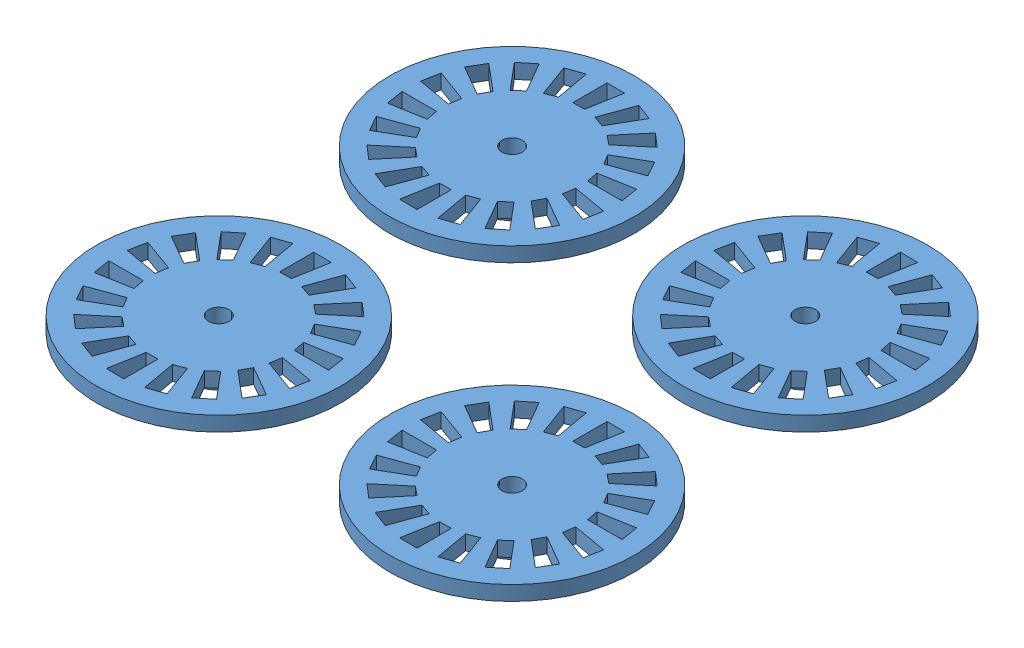
SolidWorks assembly 어셈블리1, configuration Default. Lengths in mm.
Overall size (55 4.5 55).
4 component instances, 1 part files, 6 mates.
Components (placement in the parent):
- encoder_disk-5: encoder_disk [Default] at (-7.5778 19.0131 16.6139) size (25 4.5 25)
- encoder_disk-6: encoder_disk [Default] at (22.4222 19.0131 16.6139) size (25 4.5 25)
- encoder_disk-7: encoder_disk [Default] at (-7.5778 19.0131 46.6139) size (25 4.5 25)
- encoder_disk-8: encoder_disk [Default] at (22.4222 19.0131 46.6139) size (25 4.5 25)
Mates (geometry in assembly coordinates):
- 일치18: coincident aligned: plane of encoder_disk-5 through (-7.5778 20.5131 16.6139) normal (0 1 0); plane of encoder_disk-7 through (-7.5778 20.5131 46.6139) normal (0 1 0)
- 일치19: coincident aligned: plane of encoder_disk-5 through (-7.5778 20.5131 16.6139) normal (0 1 0); plane of encoder_disk-6 through (22.4222 20.5131 16.6139) normal (0 1 0)
- 일치20: coincident aligned: plane of encoder_disk-5 through (-7.5778 20.5131 16.6139) normal (0 1 0); plane of encoder_disk-8 through (22.4222 20.5131 46.6139) normal (0 1 0)
- 동심5: concentric: cylinder of encoder_disk-7 through (-7.5778 -1.4869 46.6139) axis (0 1 0) radius 1.05; point of assembly
- 동심4: concentric: cylinder of encoder_disk-6 through (22.4222 -1.4869 16.6139) axis (0 1 0) radius 1.05; point of assembly
- 동심3: concentric: cylinder of encoder_disk-8 through (22.4222 -1.4869 46.6139) axis (0 1 0) radius 1.05; point of assembly
